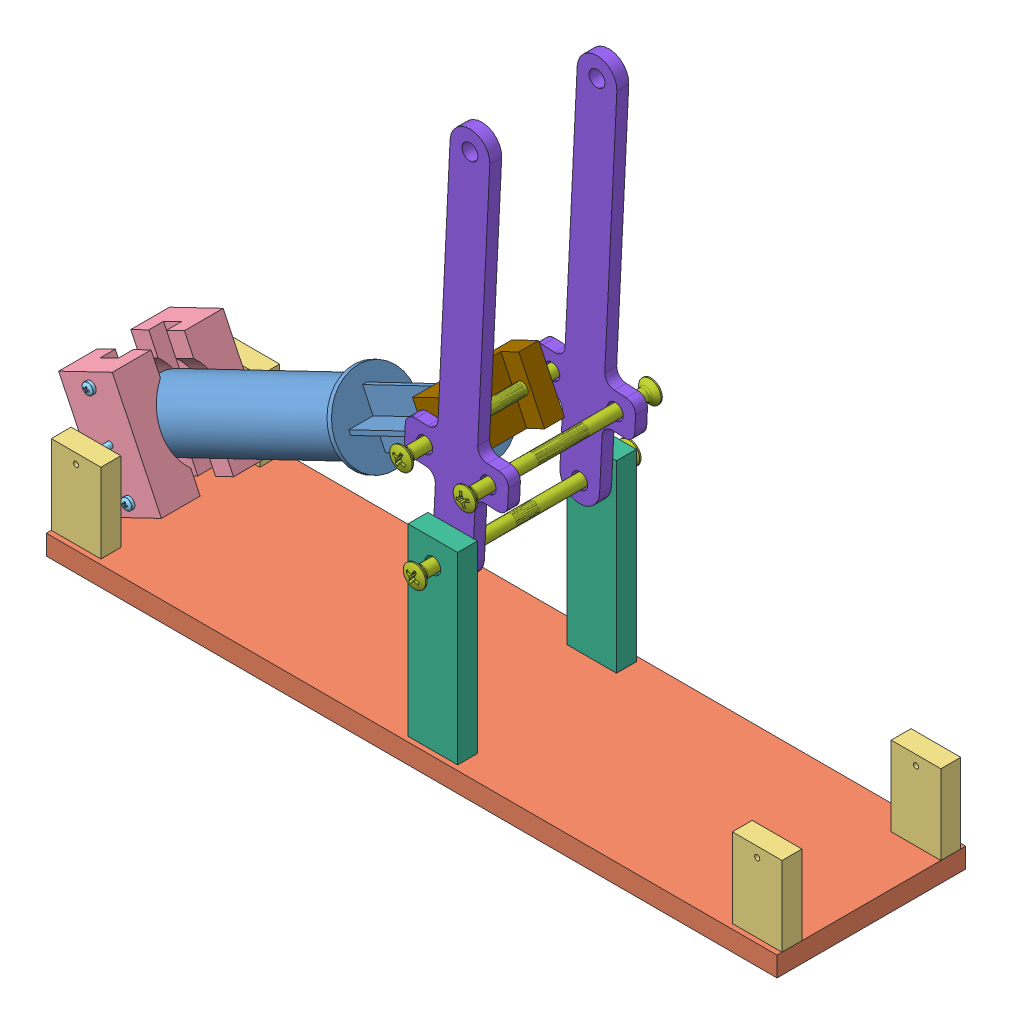
SolidWorks assembly syringepumpv0.3, configuration Default. Lengths in mm.
Overall size (381.37 281.69 111.02).
23 component instances, 9 part files, 21 mates.
Components (placement in the parent):
- seringe-1: seringe [Default] at (12.9272 94.9938 269.5242) x (0 0 1) z (-0.901107 -0.433597 0) size (41.4 41.4 171.67)
- base-1: base [Default] at (80.5296 0 269.5242) size (368 10 95)
- fulcrumsyringtip-1: fulcrumsyringtip [Default] at (-90.9704 30 304.5242) size (25 40 10)
- syringholder-1: syringholder [Default] at (-86.4649 47.168 270.4242) x (0.901107 0.433597 0) z (0 0 -1) size (30 57 19.5)
- pan head cross recess screw_iso-1: pan head cross recess screw_iso [ISO 7045 - M3 x 20 - Z - 20N] at (-100.7263 65.2749 299.8242) x (0 0 -1) z (1 0 0) size (22.35 5.6 5.6)
- pan head cross recess screw_iso-2: pan head cross recess screw_iso [ISO 7045 - M3 x 20 - Z - 20N] at (-90.9704 45 307.778) x (0 0 -1) z (0.841495 0.540265 0) size (22.35 5.6 5.6)
- pan head cross recess screw_iso-3: pan head cross recess screw_iso [ISO 7045 - M3 x 20 - Z - 20N] at (-81.2145 24.7251 299.8242) x (0 0 -1) z (1 0 0) size (22.35 5.6 5.6)
- fulcrumsyringtip-3: fulcrumsyringtip [Default] at (-90.9704 30 224.5242) size (25 40 10)
- pan head cross recess screw_iso-4: pan head cross recess screw_iso [ISO 7045 - M3 x 20 - Z - 20N] at (-90.9704 45 231.2704) x (0 0 1) z (-0.841495 -0.540265 0) size (22.35 5.6 5.6)
- syringholder-3: syringholder [Default] at (-95.4759 42.832 268.6242) x (-0.901107 -0.433597 0) z (0 0 1) size (30 57 19.5)
- fulcrumsyringepusher-1: fulcrumsyringepusher [Default] at (88.6747 56.3293 314.5242) x (-1 0 0) z (0 0 -1) size (25 92.66 10)
- countersunk raised head cross recess screw_iso-1: countersunk raised head cross recess screw_iso [ISO 7047 - M6 x 60 - Z - 38N] at (88.6747 90.6586 325.1317) x (0 0 -1) z (-0.917972 0.396644 0) size (61.3 11.3 11.3)
- LEVERARM-1: LEVERARM [Default] at (88.6747 90.6586 298.5242) x (0 0 1) z (-0.998834 0.048285 0) size (6 200 52)
- seringepusherholder-1: seringepusherholder [Default] at (68.1637 127.5147 270.4761) x (0.433597 -0.901107 0) z (-0.901107 -0.433597 0) size (30 50 15)
- countersunk raised head cross recess screw_iso-2: countersunk raised head cross recess screw_iso [ISO 7047 - M6 x 60 - Z - 38N] at (74.6247 131.3845 317.9292) x (0 0 -1) z (-0.917972 0.396644 0) size (61.3 11.3 11.3)
- fulcrumsyringepusher-2: fulcrumsyringepusher [Default] at (88.6747 56.3293 234.5242) x (-1 0 0) z (0 0 -1) size (25 92.66 10)
- LEVERARM-3: LEVERARM [Default] at (88.6747 90.6586 240.5242) x (0 0 -1) z (0.998834 -0.048285 0) size (6 200 52)
- countersunk raised head cross recess screw_iso-3: countersunk raised head cross recess screw_iso [ISO 7047 - M6 x 60 - Z - 38N] at (88.6747 90.6586 213.9167) x (0 0 1) z (0.917972 -0.396644 0) size (61.3 11.3 11.3)
- countersunk raised head cross recess screw_iso-4: countersunk raised head cross recess screw_iso [ISO 7047 - M6 x 60 - Z - 38N] at (74.6247 131.3845 221.1192) x (0 0 1) z (0.917972 -0.396644 0) size (61.3 11.3 11.3)
- fulcrumsyringtip-4: fulcrumsyringtip [Default] at (252.0296 30 314.5242) x (-1 0 0) z (0 0 -1) size (25 40 10)
- fulcrumsyringtip-5: fulcrumsyringtip [Default] at (252.0296 30 234.5242) x (-1 0 0) z (0 0 -1) size (25 40 10)
- countersunk raised head cross recess screw_iso-5: countersunk raised head cross recess screw_iso [ISO 7047 - M6 x 60 - Z - 38N] at (106.5874 129.8394 317.9292) x (0 0 -1) z (-0.951951 -0.306249 0) size (61.3 11.3 11.3)
- countersunk raised head cross recess screw_iso-6: countersunk raised head cross recess screw_iso [ISO 7047 - M6 x 60 - Z - 38N] at (106.5874 129.8394 221.1192) x (0 0 1) z (0.951951 0.306249 0) size (61.3 11.3 11.3)
Mates (geometry in assembly coordinates):
- Coincident1: coincident anti-aligned: plane of base-1 through (80.5296 10 269.5242) normal (0 1 0); plane of fulcrumsyringtip-1 through (-103.4704 10 314.5242) normal (0 -1 0)
- Distance1: distance = 45 mm aligned: plane of fulcrumsyringtip-1 through (-90.9704 30 314.5242) normal (0 0 1); plane of assembly through (0 0 269.5242) normal (0 0 1)
- Concentric1: concentric anti-aligned: cylinder of fulcrumsyringtip-1 through (-90.9704 45 314.5242) axis (0 0 -1) radius 1.3; cylinder of pan head cross recess screw_iso-2 through (-90.9704 45 333.178) axis (0 0 1) radius 1.5
- Coincident3: coincident aligned: plane of base-1 through (-103.4704 10 317.0242) normal (-1 0 0); plane of fulcrumsyringtip-1 through (-103.4704 50 314.5242) normal (-1 0 0)
- Coincident4: coincident anti-aligned: plane of base-1 through (80.5296 0 269.5242) normal (0 -1 0); plane of assembly through (0 0 0) normal (0 1 0)
- Concentric2: concentric aligned: cylinder of syringholder-1 through (-90.9704 45 277.9242) axis (0 0 1) radius 1.3; cylinder of pan head cross recess screw_iso-2 through (-90.9704 45 333.178) axis (0 0 1) radius 1.5
- Concentric3: concentric aligned: cylinder of syringholder-1 through (-81.2145 24.7251 277.9242) axis (0 0 1) radius 1.3; cylinder of pan head cross recess screw_iso-3 through (-81.2145 24.7251 325.2242) axis (0 0 1) radius 1.5
- Coincident5: coincident aligned: plane of syringholder-1 through (-77.4538 51.504 297.4242) normal (0 0 1); circle of pan head cross recess screw_iso-3
- Concentric4: concentric aligned: cylinder of syringholder-1 through (-100.7263 65.2749 277.9242) axis (0 0 1) radius 1.3; cylinder of pan head cross recess screw_iso-1 through (-100.7263 65.2749 325.2242) axis (0 0 1) radius 1.5
- Coincident6: coincident aligned: plane of syringholder-1 through (-77.4538 51.504 297.4242) normal (0 0 1); circle of pan head cross recess screw_iso-1
- Coincident8: coincident aligned: plane of seringe-1; plane of assembly through (0 0 269.5242) normal (0 0 1)
- Coincident10: coincident anti-aligned: plane of seringe-1; plane of syringholder-1
- Tangent8: tangent aligned: cylinder of seringe-1 through (-86.4649 47.168 269.5242) axis (0.901107 0.433597 0) radius 15.9; cylinder of syringholder-1 through (-77.4538 51.504 261.0492) axis (-0.901107 -0.433597 0) radius 24.375
- Coincident14: coincident aligned: plane of seringe-1 through (-86.4649 47.168 269.5242) normal (-0.901107 -0.433597 0); plane of syringholder-1 through (-86.4649 47.168 270.4242) normal (-0.901107 -0.433597 0)
- Distance3: distance = 45 mm aligned: plane of fulcrumsyringepusher-1 through (88.6747 56.3293 314.5242) normal (0 0 1); plane of assembly through (0 0 269.5242) normal (0 0 1)
- Coincident17: coincident anti-aligned: plane of base-1 through (80.5296 10 269.5242) normal (0 1 0); plane of fulcrumsyringepusher-1 through (101.1747 10 304.5242) normal (0 -1 0)
- Concentric15: concentric aligned: cylinder of fulcrumsyringepusher-1 through (88.6747 90.6586 304.5242) axis (0 0 1) radius 4; cylinder of countersunk raised head cross recess screw_iso-1 through (88.6747 90.6586 341.0067) axis (0 0 1) radius 3
- Concentric16: concentric anti-aligned: cylinder of countersunk raised head cross recess screw_iso-1 through (88.6747 90.6586 341.0067) axis (0 0 1) radius 3; cylinder of LEVERARM-1 through (88.6747 90.6586 304.5242) axis (0 0 -1) radius 4
- Coincident26: coincident anti-aligned: plane of seringe-1 through (68.2326 121.6058 269.5242) normal (0.901107 0.433597 0); plane of seringepusherholder-1 through (65.911 126.4307 270.4761) normal (-0.901107 -0.433597 0)
- Concentric20: concentric anti-aligned: cylinder of LEVERARM-1 through (74.6247 131.3845 304.5242) axis (0 0 -1) radius 4; cylinder of countersunk raised head cross recess screw_iso-2 through (74.6247 131.3845 333.8042) axis (0 0 1) radius 3
- Concentric21: concentric anti-aligned: cylinder of seringepusherholder-1 through (74.6247 131.3845 245.4761) axis (0 0 1) radius 3; cylinder of countersunk raised head cross recess screw_iso-4 through (74.6247 131.3845 205.2442) axis (0 0 -1) radius 3
